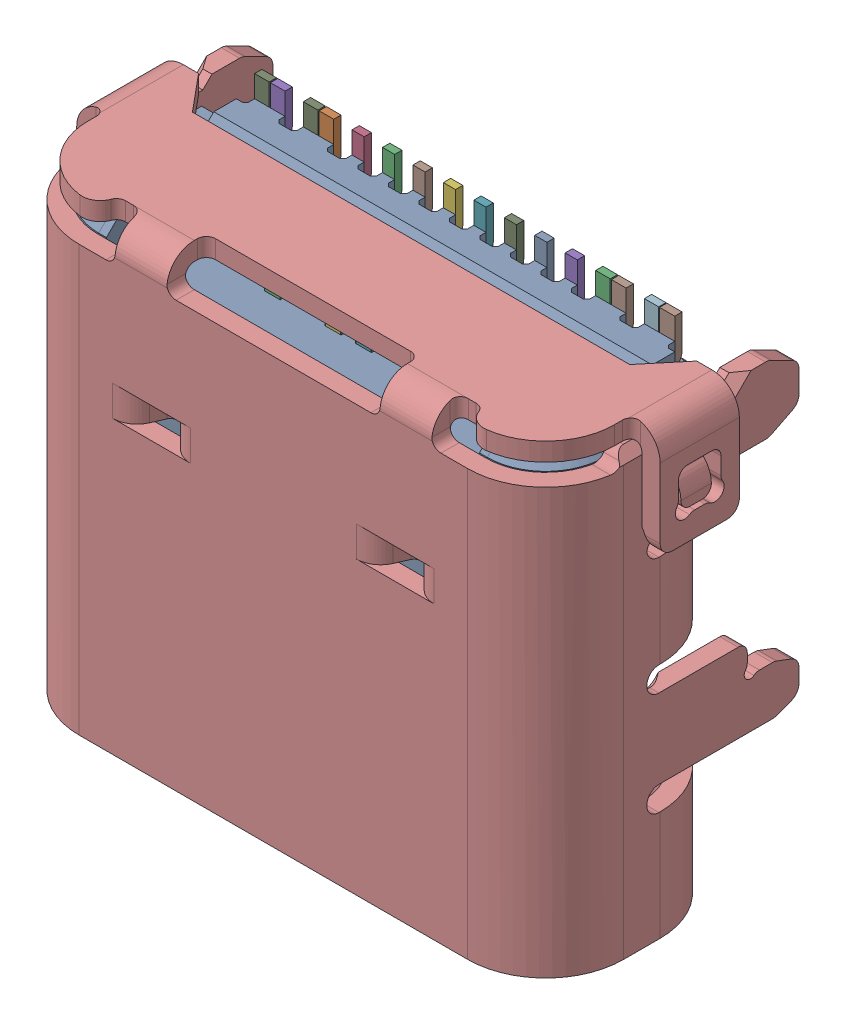
SolidWorks assembly Type_C2, configuration Default. Lengths in mm.
Overall size (9.58 7.71 4.16).
23 component instances, 22 part files, 0 mates.
Components (placement in the parent):
- 698b116-264-211-1: 698b116-264-211 [Default] at (28.1778 -5.2311 -12) x (1 0 0) z (0 -1 0) size (9.58 4.16 7.71)
  - SOLID-1: SOLID [Default] at origin size (8.34 3.56 7.05)
  - SOLID (1)-1: SOLID (1) [Default] at origin size (0.26 1.45 0.87)
  - SOLID (2)-1: SOLID (2) [Default] at origin size (0.26 1.45 0.87)
  - SOLID (3)-1: SOLID (3) [Default] at origin size (0.25 1.45 0.87)
  - SOLID (4)-1: SOLID (4) [Default] at origin size (0.25 1.45 0.87)
  - SOLID (5)-1: SOLID (5) [Default] at origin size (0.25 2.03 6.58)
  - SOLID (6)-1: SOLID (6) [Default] at origin size (0.25 2.03 6.58)
  - SOLID (7)-1: SOLID (7) [Default] at origin size (0.25 1.57 6.58)
  - SOLID (8)-1: SOLID (8) [Default] at origin size (0.25 1.57 6.58)
  - SOLID (9)-1: SOLID (9) [Default] at origin size (0.25 0.24 5.71)
  - SOLID (10)-1: SOLID (10) [Default] at origin size (0.25 0.24 5.71)
  - SOLID (11)-1: SOLID (11) [Default] at origin size (0.85 1.57 7.13)
  - SOLID (12)-1: SOLID (12) [Default] at origin size (0.35 2.03 6.78)
  - SOLID (13)-1: SOLID (13) [Default] at origin size (0.35 0.24 5.91)
  - SOLID (14)-1: SOLID (14) [Default] at origin size (0.35 2.03 6.78)
  - SOLID (15)-1: SOLID (15) [Default] at origin size (0.35 0.24 5.91)
  - SOLID (16)-1: SOLID (16) [Default] at origin size (0.85 1.57 7.13)
  - SOLID (17)-1: SOLID (17) [Default] at origin size (0.25 0.24 4.21)
  - SOLID (18)-1: SOLID (18) [Default] at origin size (0.25 0.24 4.21)
  - SOLID (19)-1: SOLID (19) [Default] at origin size (1.11 2.03 7.13)
  - SOLID (20)-1: SOLID (20) [Default] at origin size (1.12 2.03 7.13)
  - SOLID (21)-1: SOLID (21) [Default] at origin size (9.58 4.16 7.53)
